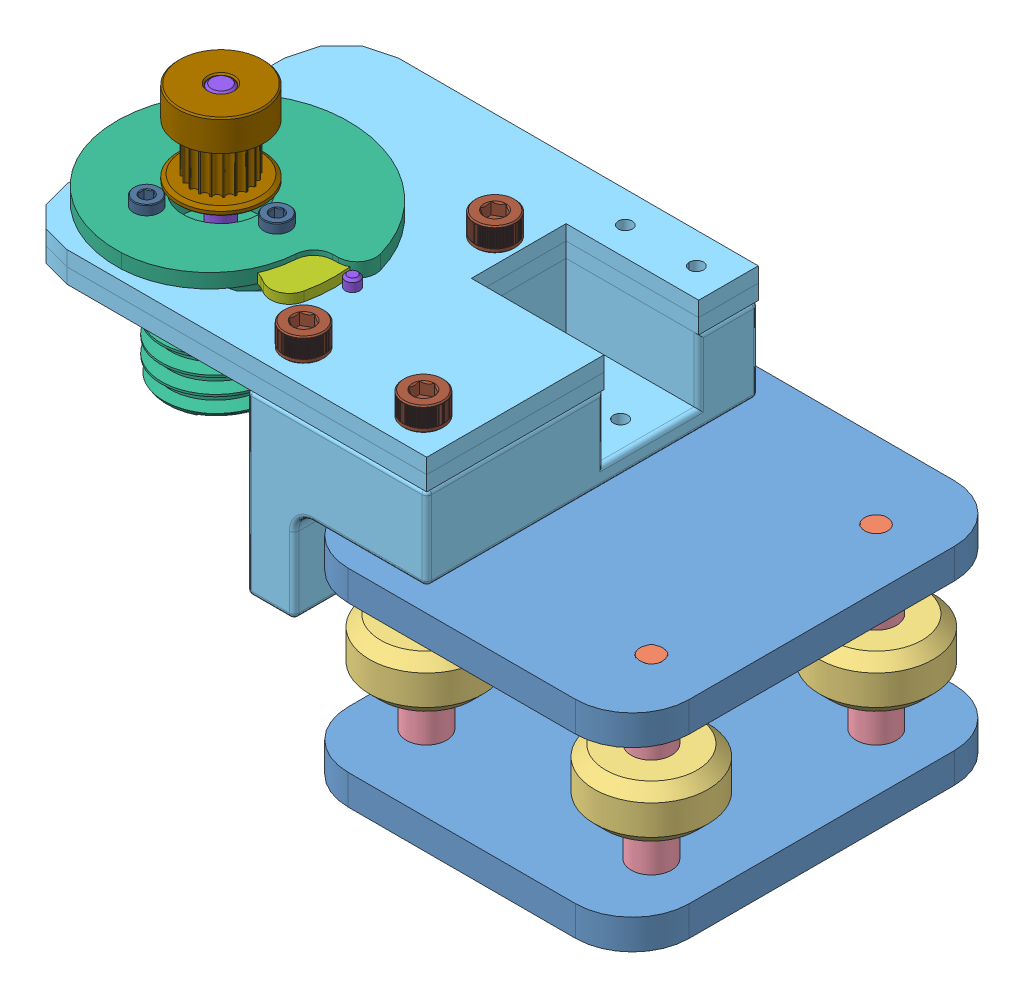
SolidWorks assembly v_wheel_carrage_right, configuration Default. Lengths in mm.
Overall size (146.57 91.02 82.45).
31 component instances, 11 part files, 37 mates.
Components (placement in the parent):
- v_wheel_carrage-1: v_wheel_carrage [Default] at (25.1366 33.0831 59.2346) size (72 6.35 80)
- shaft-2: shaft [Default] at (1.3866 76.7831 82.9846) x (-0.624188 0 0.781274) z (0.781274 0 0.624188) size (5 43.7 5)
- v_wheel-2: v_wheel [Default] at (1.3866 60.4331 82.9846) x (0.968872 0 -0.247564) z (0 1 0) size (24 24 11)
- spacer-4: spacer [Default] at (1.3866 70.4331 82.9846) x (1 0 0) z (0 -1 0) size (8.5 8.5 10)
- spacer-5: spacer [Default] at (1.3866 49.4331 82.9846) x (1 0 0) z (0 -1 0) size (8.5 8.5 10)
- v_wheel_carrage-2: v_wheel_carrage [m_plate] at (25.1366 76.7831 59.2346) x (1 0 0) z (0 0 -1) size (72 6.35 80)
- v_wheel-7: v_wheel [Default] at (1.3866 60.4331 35.4846) x (0.968872 0 -0.247564) z (0 1 0) size (24 24 11)
- v_wheel-8: v_wheel [Default] at (48.8866 60.4331 82.9846) x (0.968872 0 -0.247564) z (0 1 0) size (24 24 11)
- v_wheel-9: v_wheel [Default] at (48.8866 60.4331 35.4846) x (0.968872 0 -0.247564) z (0 1 0) size (24 24 11)
- spacer-6: spacer [Default] at (1.3866 70.4331 35.4846) x (1 0 0) z (0 -1 0) size (8.5 8.5 10)
- spacer-7: spacer [Default] at (48.8866 70.4331 82.9846) x (1 0 0) z (0 -1 0) size (8.5 8.5 10)
- spacer-8: spacer [Default] at (48.8866 70.4331 35.4846) x (1 0 0) z (0 -1 0) size (8.5 8.5 10)
- spacer-9: spacer [Default] at (1.3866 49.4331 35.4846) x (1 0 0) z (0 -1 0) size (8.5 8.5 10)
- spacer-10: spacer [Default] at (48.8866 49.4331 82.9846) x (1 0 0) z (0 -1 0) size (8.5 8.5 10)
- spacer-11: spacer [Default] at (48.8866 49.4331 35.4846) x (1 0 0) z (0 -1 0) size (8.5 8.5 10)
- shaft-8: shaft [Default] at (1.3866 76.7831 35.4846) x (-0.624188 0 0.781274) z (0.781274 0 0.624188) size (5 43.7 5)
- shaft-9: shaft [Default] at (48.8866 76.7831 82.9846) x (-0.624188 0 0.781274) z (0.781274 0 0.624188) size (5 43.7 5)
- shaft-10: shaft [Default] at (48.8866 76.7831 35.4846) x (-0.624188 0 0.781274) z (0.781274 0 0.624188) size (5 43.7 5)
- x_axis_tensioner_mount_V1-1: x_axis_tensioner_mount_V1 [Default] at (13.1366 76.7831 94.6612) x (-1 0 0) z (0 0 -1) size (88 44 70)
- bearing_can-1: bearing_can [Default] at (-53.6367 71.1081 71.3346) x (0.022718 0 0.999742) z (-0.999742 0 0.022718) size (38 34.26 41.53)
- cam-1: cam [Default] at (-53.6367 101.1081 71.3346) x (-0.480196 0 0.877161) z (-0.877161 0 -0.480196) size (45 2 49.3)
- axel_pin-1: axel_pin [cam_follower] at (-25.8634 89.6864 71.3346) size (3 10 3)
- 3684N13_Corrosion-Resistant HTD Timing Belt Pulley-1: 3684N13_Corrosion-Resistant HTD Timing Belt Pulley [3684N13] at (-53.6367 117.1081 71.3346) x (0.064052 0 0.997947) z (0 -1 0) size (18 18 18)
- axel_pin-2: axel_pin [Default] at (-53.6367 74.1081 71.3346) x (0.99996 0 -0.008914) z (0.008914 0 0.99996) size (5 50 5)
- 91290A572_Black-Oxide Alloy Steel Socket Head Screw-2: 91290A572_Black-Oxide Alloy Steel Socket Head Screw [10] at (-42.0927 99.6081 71.0722) x (1 0 0) z (0 1 0) size (5.5 5.5 13)
- 91290A572_Black-Oxide Alloy Steel Socket Head Screw-3: 91290A572_Black-Oxide Alloy Steel Socket Head Screw [10] at (-59.6359 99.6081 61.4683) x (1 0 0) z (0 1 0) size (5.5 5.5 13)
- 91290A572_Black-Oxide Alloy Steel Socket Head Screw-4: 91290A572_Black-Oxide Alloy Steel Socket Head Screw [10] at (-59.1816 99.6081 81.4631) x (1 0 0) z (0 1 0) size (5.5 5.5 13)
- 91290A231_Alloy Steel Socket Head Screw-2: 91290A231_Alloy Steel Socket Head Screw [91290A231] at (-19.8634 95.7831 87.6397) x (1 0 0) z (0 1 0) size (8.5 8.5 20.34)
- 91290A231_Alloy Steel Socket Head Screw-3: 91290A231_Alloy Steel Socket Head Screw [91290A231] at (5.4082 95.7831 87.6397) x (1 0 0) z (0 1 0) size (8.5 8.5 20.34)
- 91290A231_Alloy Steel Socket Head Screw-4: 91290A231_Alloy Steel Socket Head Screw [91290A231] at (-19.8634 95.7831 47.2346) x (1 0 0) z (0 1 0) size (8.5 8.5 20.34)
- axel_pin-5: axel_pin [cam_follower] at (-25.8634 93.1081 71.3346) x (0.99996 0 -0.008914) z (0.008914 0 0.99996) size (3 10 3)
Mates (geometry in assembly coordinates):
- Concentric11: concentric aligned: cylinder of v_wheel_carrage-1 through (1.3866 33.0831 82.9846) axis (0 1 0) radius 2.4; cylinder of shaft-2 through (1.3866 33.0831 82.9846) axis (0 1 0) radius 2.5
- Concentric71: concentric aligned: cylinder of shaft-2 through (1.3866 33.0831 82.9846) axis (0 1 0) radius 2.5; cylinder of v_wheel-2 through (1.3866 60.4331 82.9846) axis (0 1 0) radius 2.5
- Concentric131: concentric aligned: cylinder of shaft-2 through (1.3866 33.0831 82.9846) axis (0 1 0) radius 2.5; cylinder of spacer-4 through (1.3866 60.4331 82.9846) axis (0 1 0) radius 2.75
- Concentric141: concentric aligned: cylinder of shaft-2 through (1.3866 33.0831 82.9846) axis (0 1 0) radius 2.5; cylinder of spacer-5 through (1.3866 39.4331 82.9846) axis (0 1 0) radius 2.75
- Coincident1: coincident anti-aligned: plane of v_wheel-2 through (3.8088 60.4331 82.3657) normal (0 1 0); plane of spacer-4 through (1.3866 60.4331 82.9846) normal (0 -1 0)
- Coincident2: coincident anti-aligned: plane of v_wheel-2 through (10.7362 49.4331 80.5956) normal (0 -1 0); plane of spacer-5 through (1.3866 49.4331 82.9846) normal (0 1 0)
- Coincident3: coincident anti-aligned: plane of v_wheel_carrage-1 through (49.1366 39.4331 31.2346) normal (0 1 0); plane of spacer-5 through (1.3866 39.4331 82.9846) normal (0 -1 0)
- Coincident10: coincident aligned: plane of v_wheel_carrage-1 through (1.1366 39.4331 99.2346) normal (0 0 1); plane of v_wheel_carrage-2 through (1.1366 70.4331 99.2346) normal (0 0 1)
- Coincident12: coincident aligned: plane of v_wheel_carrage-1 through (61.1366 39.4331 87.2346) normal (1 0 0); plane of v_wheel_carrage-2 through (61.1366 70.4331 31.2346) normal (1 0 0)
- Coincident13: coincident anti-aligned: plane of v_wheel_carrage-2 through (49.1366 70.4331 87.2346) normal (0 -1 0); plane of spacer-7 through (48.8866 70.4331 82.9846) normal (0 1 0)
- Coincident14: coincident aligned: plane of shaft-2 through (1.3866 76.7831 82.9846) normal (0 1 0); plane of v_wheel_carrage-2 through (49.1366 76.7831 87.2346) normal (0 1 0)
- Concentric143: concentric aligned: cylinder of v_wheel_carrage-2 through (6.6366 76.7831 47.2346) axis (0 -1 0) radius 1.5; cylinder of x_axis_tensioner_mount_V1-1 through (6.6366 100.7831 47.2346) axis (0 -1 0) radius 1.5
- Concentric144: concentric aligned: cylinder of v_wheel_carrage-2 through (-8.3634 76.7831 47.2346) axis (0 -1 0) radius 1.5; cylinder of x_axis_tensioner_mount_V1-1 through (-8.3634 100.7831 47.2346) axis (0 -1 0) radius 1.5
- Coincident15: coincident anti-aligned: plane of v_wheel_carrage-2 through (49.1366 76.7831 87.2346) normal (0 1 0); plane of x_axis_tensioner_mount_V1-1 through (-14.8634 76.7831 24.6612) normal (0 -1 0)
- Slot1: slot anti-aligned: cylinder of bearing_can-1 through (-53.6367 71.1081 71.3346) axis (0 -1 0) radius 12; cylinder of x_axis_tensioner_mount_V1-1 through (-54.8634 56.7831 71.3346) axis (0 1 0) radius 10; cylinder of x_axis_tensioner_mount_V1-1 through (-44.8634 56.7831 71.3346) axis (0 1 0) radius 10
- Coincident16: coincident anti-aligned: plane of x_axis_tensioner_mount_V1-1 through (-44.8634 97.6081 56.3346) normal (0 1 0); plane of bearing_can-1 through (-36.6411 97.6081 70.9484) normal (0 -1 0)
- Concentric146: concentric anti-aligned: cylinder of bearing_can-1 through (-53.6367 71.1081 71.3346) axis (0 -1 0) radius 8; cylinder of cam-1 through (-53.6367 101.1081 71.3346) axis (0 1 0) radius 9
- Coincident17: coincident aligned: circle of x_axis_tensioner_mount_V1-1; cylinder of axel_pin-1 through (-25.8634 99.6864 71.3346) axis (0 -1 0) radius 1.5
- CamMateTangent1: cam tangent anti-aligned: cylinder of cam-1 through (-55.9863 103.1081 70.0483) axis (0 -1 0) radius 20.1786; cylinder of axel_pin-1 through (-25.8634 99.6864 71.3346) axis (0 -1 0) radius 1.5
- Concentric148: concentric aligned: cylinder of bearing_can-1 through (-53.6367 71.1081 71.3346) axis (0 -1 0) radius 3; cylinder of axel_pin-2 through (-53.6367 124.1081 71.3346) axis (0 -1 0) radius 2.5
- Concentric149: concentric aligned: cylinder of 3684N13_Corrosion-Resistant HTD Timing Belt Pulley-1 through (-53.6367 106.1081 71.3346) axis (0 -1 0) radius 2.5; cylinder of axel_pin-2 through (-53.6367 124.1081 71.3346) axis (0 -1 0) radius 2.5
- Concentric1501: concentric anti-aligned: cylinder of cam-1 through (-42.0927 101.1081 71.0722) axis (0 1 0) radius 1.5; cone of 91290A572_Black-Oxide Alloy Steel Socket Head Screw-2 through (-42.0927 103.1081 71.0722) axis (0 -1 0)
- Coincident191: coincident anti-aligned: plane of cam-1 through (-54.8973 103.1081 73.6371) normal (0 1 0); plane of 91290A572_Black-Oxide Alloy Steel Socket Head Screw-2 through (-42.0927 103.1081 68.4722) normal (0 -1 0)
- Concentric1511: concentric anti-aligned: cylinder of cam-1 through (-59.6359 101.1081 61.4683) axis (0 1 0) radius 1.5; cone of 91290A572_Black-Oxide Alloy Steel Socket Head Screw-3 through (-59.6359 103.1081 61.4683) axis (0 -1 0)
- Coincident201: coincident anti-aligned: plane of cam-1 through (-54.8973 103.1081 73.6371) normal (0 1 0); plane of 91290A572_Black-Oxide Alloy Steel Socket Head Screw-3 through (-59.6359 103.1081 58.8683) normal (0 -1 0)
- Concentric1521: concentric anti-aligned: cylinder of cam-1 through (-59.1816 101.1081 81.4631) axis (0 1 0) radius 1.5; cone of 91290A572_Black-Oxide Alloy Steel Socket Head Screw-4 through (-59.1816 103.1081 81.4631) axis (0 -1 0)
- Coincident211: coincident anti-aligned: plane of cam-1 through (-54.8973 103.1081 73.6371) normal (0 1 0); plane of 91290A572_Black-Oxide Alloy Steel Socket Head Screw-4 through (-59.1816 103.1081 78.8631) normal (0 -1 0)
- Concentric1531: concentric aligned: cylinder of x_axis_tensioner_mount_V1-1 through (-19.8634 100.7831 87.6397) axis (0 -1 0) radius 2.5; cone of 91290A231_Alloy Steel Socket Head Screw-2 through (-19.8634 100.7831 87.6397) axis (0 -1 0)
- Coincident221: coincident anti-aligned: plane of x_axis_tensioner_mount_V1-1 through (13.1366 100.7831 24.6612) normal (0 1 0); plane of 91290A231_Alloy Steel Socket Head Screw-2 through (-23.8634 100.7831 87.6397) normal (0 -1 0)
- Concentric1541: concentric aligned: cylinder of x_axis_tensioner_mount_V1-1 through (5.4082 100.7831 87.6397) axis (0 -1 0) radius 2.5; cone of 91290A231_Alloy Steel Socket Head Screw-3 through (5.4082 100.7831 87.6397) axis (0 -1 0)
- Coincident231: coincident anti-aligned: plane of x_axis_tensioner_mount_V1-1 through (13.1366 100.7831 24.6612) normal (0 1 0); plane of 91290A231_Alloy Steel Socket Head Screw-3 through (1.4082 100.7831 87.6397) normal (0 -1 0)
- Concentric1551: concentric aligned: cylinder of x_axis_tensioner_mount_V1-1 through (-19.8634 100.7831 47.2346) axis (0 -1 0) radius 2.5; cone of 91290A231_Alloy Steel Socket Head Screw-4 through (-19.8634 100.7831 47.2346) axis (0 -1 0)
- Coincident241: coincident anti-aligned: plane of x_axis_tensioner_mount_V1-1 through (13.1366 100.7831 24.6612) normal (0 1 0); plane of 91290A231_Alloy Steel Socket Head Screw-4 through (-23.8634 100.7831 47.2346) normal (0 -1 0)
- Concentric1561: concentric aligned: cylinder of x_axis_tensioner_mount_V1-1 through (-25.8634 100.7831 71.3346) axis (0 -1 0) radius 1.5; cylinder of axel_pin-5 through (-25.8634 103.1081 71.3346) axis (0 -1 0) radius 1.5
- Coincident25: coincident aligned: plane of cam-1 through (-54.8973 103.1081 73.6371) normal (0 1 0); plane of axel_pin-5 through (-25.8634 103.1081 71.3346) normal (0 1 0)
- Coincident26: coincident aligned: plane of 3684N13_Corrosion-Resistant HTD Timing Belt Pulley-1 through (-62.6183 124.1081 71.911) normal (0 1 0); plane of axel_pin-2 through (-53.6367 124.1081 71.3346) normal (0 1 0)
- Coincident27: coincident anti-aligned: plane of 3684N13_Corrosion-Resistant HTD Timing Belt Pulley-1 through (-56.1316 106.1081 71.4947) normal (0 -1 0); plane of 91290A572_Black-Oxide Alloy Steel Socket Head Screw-4 through (-59.1816 106.1081 81.4631) normal (0 1 0)
